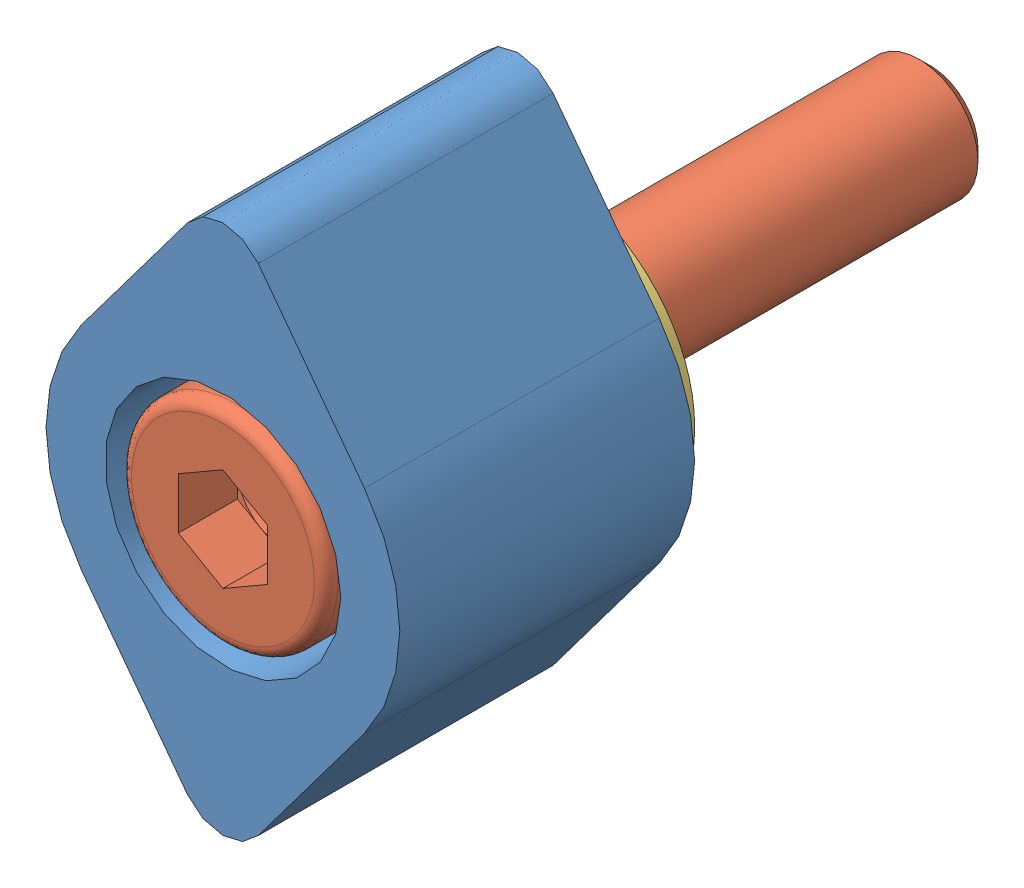
SolidWorks assembly thumb_flag_screw, configuration По умолчанию. Lengths in mm.
Overall size (12 18 24).
3 component instances, 3 part files, 4 mates.
Components (placement in the parent):
- thumb_flag-1: thumb_flag [По умолчанию] at (-71.4451 35.3578 31.093) size (12 18 10)
- socket head cap screw_din-1: socket head cap screw_din [DIN 912 M4 x 20 --- 20N] at (-71.4451 35.3578 41.093) x (0 0 -1) z (1 0 0) size (24 7 7)
- plain washer 6902 type abc_din-1: plain washer 6902 type abc_din [DIN 6902-A4.55] at (-71.4451 35.3578 31.093) x (0 0 -1) z (1 0 0) size (1 10 10)
Mates (geometry in assembly coordinates):
- Концентричный1: concentric aligned: cylinder of thumb_flag-1 through (-71.4451 35.3578 37.093) axis (0 0 1) radius 1.65; cylinder of socket head cap screw_din-1 through (-71.4451 35.3578 72.843) axis (0 0 1) radius 3.5
- Совпадение1: coincident anti-aligned: plane of thumb_flag-1 through (-71.4451 35.3578 37.093) normal (0 0 1); plane of socket head cap screw_din-1 through (-71.4451 38.8578 37.093) normal (0 0 -1)
- Концентричный2: concentric aligned: cylinder of socket head cap screw_din-1 through (-71.4451 35.3578 72.843) axis (0 0 1) radius 2; cylinder of plain washer 6902 type abc_din-1 through (-71.4451 35.3578 26.7663) axis (0 0 1) radius 2.275
- Совпадение2: coincident anti-aligned: plane of thumb_flag-1 through (-71.4451 35.3578 31.093) normal (0 0 -1); plane of plain washer 6902 type abc_din-1 through (-71.4451 35.3578 31.093) normal (0 0 1)
